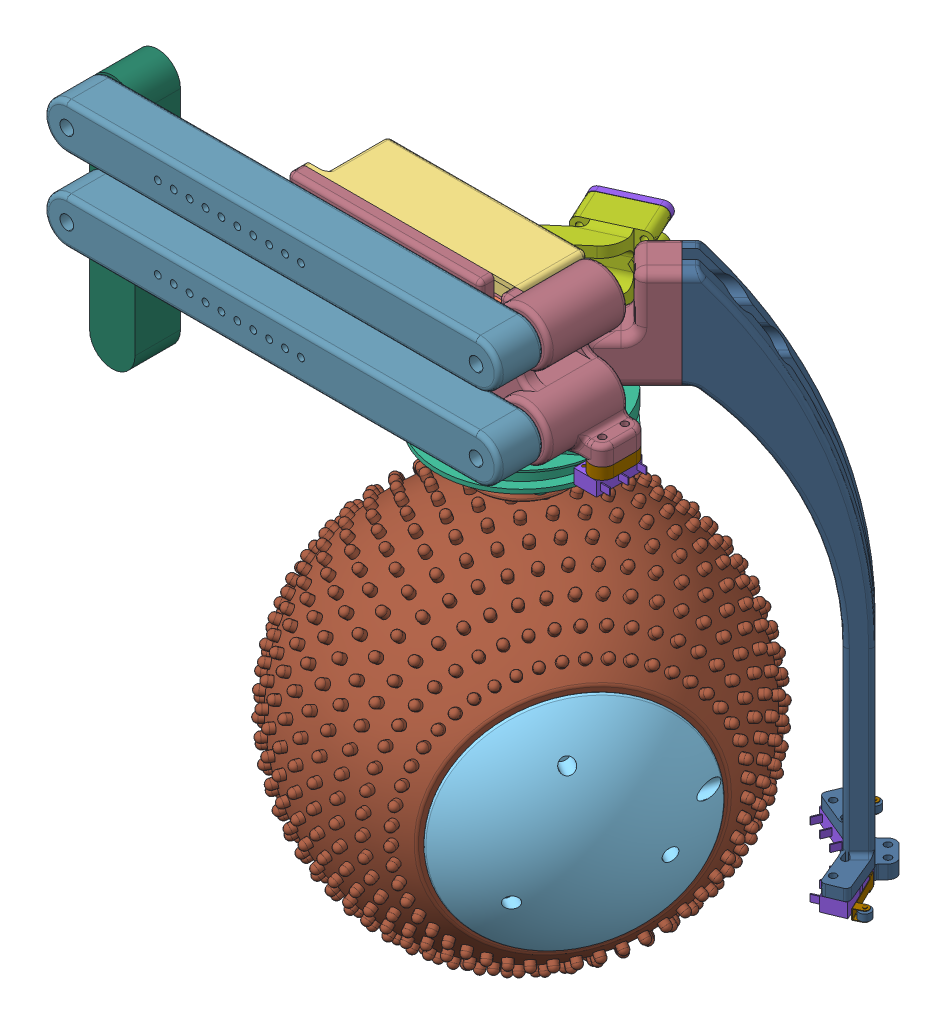
SolidWorks assembly _OmniWheel, configuration Default. Lengths in mm.
Overall size (257.35 285.35 230.93).
42 component instances, 28 part files, 105 mates.
Components (placement in the parent):
- 10mmThreadedRod-1: 10mmThreadedRod [Default] at (71.9678 -158.25 -77.1045) x (0.033468 -0.997752 -0.058051) z (0.498338 0.067008 -0.864389) size (9.53 70 9.53)
- arduino-1: arduino [Valor predeterminado] at (148.41 -2.75 -21) x (-1 0 0) z (0 0 -1) size (45.18 4.5 17.78)
- DriveMotor-1: DriveMotor [Default] at (153.4035 -158.25 -30.1552) x (-0.264151 0.848701 0.458182) z (0.423893 0.528873 -0.735261) size (25 86.5 25)
- hollowThreadedNut-1: hollowThreadedNut [Default] at (110.5631 -158.25 -54.8536) x (-0.092382 -0.982745 0.16024) z (0.490843 -0.184963 -0.851388) size (16.17 2.5 14)
- L298N Motor Driver arduino-1: L298N Motor Driver arduino [Default] at (96.25 -2.5 -9.5) x (0 1 0) z (-1 0 0) size (43.5 26 43.5)
- n20 m4x55 encoder v2-1: n20 m4x55 encoder v2 [Default] at (131.4749 -29.5 -92.3762) x (-0.417468 0 -0.908691) z (0 -1 0) size (12 10 42.21)
- slip_ring-1: slip_ring [Default] at (145 -53 -35) x (0.999063 0 0.043268) z (-0.043268 0 0.999063) size (23.5 17.5 23.5)
- switch_body-1: switch_body [Default] at (198 -38.125 -25) x (0 0 -1) z (0 1 0) size (20 14 6.25)
- switch_lever-1: switch_lever [Default] at (187.7929 -38.125 -26.5353) x (0.019708 0 -0.999806) z (0 1 0) size (20 8.75 6)
- switch_wheel-1: switch_wheel [Default] at (184.3312 -38 -34.8551) x (-0.999947 0 -0.010277) z (0 1 0) size (5 5 3)
- sphere_wheel-1: sphere_wheel [Default] at (145 -158.25 -35) x (-0.866337 0 -0.499461) z (0.492131 0.170683 -0.853624) size (125.5 168 168)
- motorMount-1: motorMount [Default] at (130.9004 -158.25 -43.1287) x (0.446555 -0.447916 -0.77457) z (-0.223716 -0.894076 0.388046) size (31.75 83.44 31.75)
- hollowThreadedNut-2: hollowThreadedNut [Default] at (123.7314 -158.25 -47.2618) x (-0.092382 -0.982745 0.16024) z (0.490843 -0.184963 -0.851388) size (16.17 2.5 14)
- hollowThreadedNut-4: hollowThreadedNut [Default] at (71.1448 -158.25 -77.579) x (0.01495 -0.999552 -0.025931) z (0.499237 0.029932 -0.865948) size (16.17 2.5 14)
- hollowThreadedNut-5: hollowThreadedNut [Default] at (87.172 -158.25 -68.339) x (0.24973 -0.866025 -0.433168) z (0.432546 0.5 -0.75027) size (16.17 2.5 14)
- suspension_mount-1: suspension_mount [Default] at (145 -30 -35) x (0 0 1) z (0 1 0) size (77.43 128.5 61.17)
- suspension_bar-1: suspension_bar [Default] at (180 18 10) size (200 20 20)
- suspension_mount_body-1: suspension_mount_body [Default] at origin size (20 111.88 20)
- bearing2-1: bearing2 [Default] at (106.448 -158.25 -57.226) x (0.296277 0.805059 -0.513906) z (0.402095 -0.593194 -0.697452) size (25 7 25)
- Wheel_cap-1: Wheel_cap [Default] at (109.4802 -158.25 -55.4779) x (0.08525 -0.985326 -0.147869) z (0.492131 0.170683 -0.853624) size (59.5 22.5 59.5)
- washer1-1: washer1 [Default] at (101.1417 -158.25 -60.2852) x (-0.362018 -0.68894 0.627937) z (0.344098 -0.724818 -0.596854) size (25 2.25 25)
- SpongeRing-1: SpongeRing [Default] at (96.052 -158.25 -63.2195) x (-0.866337 0 -0.499461) z (0.488344 -0.20981 -0.847054) size (14 51.5 51.5)
- wheel_arm-1: wheel_arm [Default] at (87.8218 -158.25 -67.9644) x (-0.866337 0 -0.499461) z (0.499461 0 -0.866337) size (108.38 170.79 80.42)
- suspension_bar-3: suspension_bar [Default] at (180 -18 10) size (200 20 20)
- suspension_mount_lid-1: suspension_mount_lid [Default] at (120 -2.5 -39) x (1 0 0) z (0 0 -1) size (96 55 30)
- bearing3-1: bearing3 [Default] at (145 -37.25 -35) x (0.997463 0 -0.071184) z (0 -1 0) size (28.5 28.5 9.5)
- 10mmThreadedRod-2: 10mmThreadedRod [short] at (145 -15 -35) x (0.211057 0 0.977474) z (-0.977474 0 0.211057) size (9.53 36 9.53)
- hollowThreadedNut-6: hollowThreadedNut [Default] at (145 -11.75 -35) x (-0.864079 0 0.503356) z (0.503356 0 0.864079) size (16.17 2.5 14)
- hollowThreadedNut-7: hollowThreadedNut [Default] at (145 -31.25 -35) x (-0.864079 0 0.503356) z (0.503356 0 0.864079) size (16.17 2.5 14)
- hollowThreadedNut-8: hollowThreadedNut [Default] at (145 -43.25 -35) x (-0.864079 0 0.503356) z (0.503356 0 0.864079) size (16.17 2.5 14)
- wheel_cap_2-1: wheel_cap_2 [Default] at (144.7834 -158.25 -35.1249) x (0.866337 0 0.499461) z (-0.08525 0.985326 0.147869) size (17.75 96.67 96.67)
- large_timing_pully-1: large_timing_pully [Default] at (145 -43 -35) x (-0.866337 0 -0.499461) z (0.499461 0 -0.866337) size (73.67 25.42 73.67)
- micro_gear_motor_casing_A-1: micro_gear_motor_casing_A [Default] at (131.4529 -22 -92.3705) x (-0.417468 0 -0.908691) z (0.908691 0 -0.417468) size (33.5 37.27 49.25)
- micro_gear_motor_casing_B-1: micro_gear_motor_casing_B [Default] at (128.2175 -22 -99.4128) x (-0.908691 0 0.417468) z (-0.417468 0 -0.908691) size (28.5 37.25 3)
- switch_spacer-1: switch_spacer [Default] at (195.5 -32.5 -25) x (0 0 -1) z (1 0 0) size (20 5 10)
- sensorArray_frame-1: sensorArray_frame [Default] at (180.3553 -7.5 -70.3553) x (-0.707107 0 0.707107) z (-0.707107 0 -0.707107) size (67.99 233.5 54.5)
- switch_body-2: switch_body [Default] at (202.791 -215.625 -113.7167) x (-0.92388 0 -0.382683) z (0 -1 0) size (20 14 6.25)
- switch_lever-2: switch_lever [Default] at (206.7215 -215.625 -125.3908) x (-0.810364 0 -0.585927) z (0 -1 0) size (20 8.75 6)
- switch_wheel-2: switch_wheel [Default] at (202.16 -215.625 -133.1622) x (0.999993 0 -0.003676) z (0 -1 0) size (5 5 3)
- switch_body-3: switch_body [Default] at (223.7167 -215.625 -92.791) x (0.382683 0 0.92388) z (0 1 0) size (20 14 6.25)
- switch_lever-3: switch_lever [Default] at (234.3073 -215.625 -95.6971) x (0.439028 0 0.898473) z (0 1 0) size (20 8.75 6)
- switch_wheel-3: switch_wheel [Default] at (241.1863 -215.625 -89.8762) x (-0.999993 0 -0.003746) z (0 1 0) size (5 5 3)
Mates (geometry in assembly coordinates):
- Concentric1: concentric aligned: cylinder of DriveMotor-1 through (197.1535 -158.25 -4.9325) axis (-0.866337 0 -0.499461) radius 12.5; cylinder of sphere_wheel-1 through (208.2426 -158.25 1.4606) axis (-0.866337 0 -0.499461) radius 25
- Concentric2: concentric aligned: cylinder of DriveMotor-1 through (173.7624 -158.25 -18.4179) axis (-0.866337 0 -0.499461) radius 12.2; cylinder of motorMount-1 through (183.9323 -158.25 -12.5547) axis (-0.866337 0 -0.499461) radius 12.7
- Concentric4: concentric aligned: cylinder of 10mmThreadedRod-1 through (15.6559 -158.25 -109.5695) axis (0.866337 0 0.499461) radius 4.7625; cylinder of motorMount-1 through (111.646 -158.25 -54.2292) axis (0.866337 0 0.499461) radius 4.7625
- Concentric5: concentric aligned: cylinder of 10mmThreadedRod-1 through (15.6559 -158.25 -109.5695) axis (0.866337 0 0.499461) radius 4.7625; cylinder of hollowThreadedNut-1 through (109.4802 -158.25 -55.4779) axis (0.866337 0 0.499461) radius 5
- Concentric6: concentric aligned: cylinder of 10mmThreadedRod-1 through (15.6559 -158.25 -109.5695) axis (0.866337 0 0.499461) radius 4.7625; cylinder of hollowThreadedNut-2 through (122.6485 -158.25 -47.8861) axis (0.866337 0 0.499461) radius 5
- Coincident1: coincident anti-aligned: plane of motorMount-1 through (122.6485 -158.25 -47.8861) normal (0.866337 0 0.499461); plane of hollowThreadedNut-2 through (122.6485 -158.25 -47.8861) normal (-0.866337 0 -0.499461)
- Coincident2: coincident anti-aligned: plane of hollowThreadedNut-1 through (111.646 -158.25 -54.2292) normal (0.866337 0 0.499461); plane of motorMount-1 through (111.646 -158.25 -54.2292) normal (-0.866337 0 -0.499461)
- Concentric9: concentric aligned: cylinder of 10mmThreadedRod-1 through (15.6559 -158.25 -109.5695) axis (0.866337 0 0.499461) radius 4.7625; cylinder of hollowThreadedNut-4 through (70.0619 -158.25 -78.2033) axis (0.866337 0 0.499461) radius 5
- Concentric10: concentric aligned: cylinder of 10mmThreadedRod-1 through (15.6559 -158.25 -109.5695) axis (0.866337 0 0.499461) radius 4.7625; cylinder of hollowThreadedNut-5 through (86.0891 -158.25 -68.9633) axis (0.866337 0 0.499461) radius 5
- Concentric11: concentric aligned: cylinder of switch_body-1 through (189.5 -35 -18) axis (0 -1 0) radius 0.75; cylinder of switch_lever-1 through (189.5 -36.125 -18) axis (0 -1 0) radius 1.5
- Width1: width anti-aligned: plane of switch_body-1 through (198 -41.25 -25) normal (0 -1 0); plane of switch_lever-1 through (198 -35 -25) normal (0 1 0); plane of switch_body-1 through (187.7799 -40.875 -19.5342) normal (0 1 0); plane of switch_lever-1 through (187.7799 -35.375 -19.5342) normal (0 -1 0)
- Concentric12: concentric aligned: cylinder of switch_lever-1 through (184.3312 -35.625 -34.8551) axis (0 -1 0) radius 0.75; cylinder of switch_wheel-1 through (184.3312 -36.5 -34.8551) axis (0 -1 0) radius 2.5
- Concentric18: concentric anti-aligned: cylinder of 10mmThreadedRod-1 through (15.6559 -158.25 -109.5695) axis (0.866337 0 0.499461) radius 4.7625; cylinder of bearing2-1 through (109.4802 -158.25 -55.4779) axis (-0.866337 0 -0.499461) radius 5
- Coincident24: coincident anti-aligned: plane of hollowThreadedNut-1 through (109.4802 -158.25 -55.4779) normal (-0.866337 0 -0.499461); plane of bearing2-1 through (109.4802 -158.25 -55.4779) normal (0.866337 0 0.499461)
- Concentric19: concentric anti-aligned: cylinder of bearing2-1 through (109.4802 -158.25 -55.4779) axis (-0.866337 0 -0.499461) radius 11; cylinder of Wheel_cap-1 through (89.9876 -158.25 -66.7157) axis (0.866337 0 0.499461) radius 11.125
- Coincident25: coincident anti-aligned: plane of bearing2-1 through (108.1807 -158.25 -56.2271) normal (-0.866337 0 -0.499461); plane of Wheel_cap-1 through (108.1807 -158.25 -56.2271) normal (0.866337 0 0.499461)
- Parallel1: parallel anti-aligned: plane of sphere_wheel-1 through (145 -158.25 -35) normal (-0.08525 0.985326 0.147869); plane of Wheel_cap-1 through (109.4802 -158.25 -55.4779) normal (0.08525 -0.985326 -0.147869)
- Concentric20: concentric aligned: cylinder of 10mmThreadedRod-1 through (15.6559 -158.25 -109.5695) axis (0.866337 0 0.499461) radius 4.7625; cylinder of washer1-1 through (100.1671 -158.25 -60.8471) axis (0.866337 0 0.499461) radius 5.75
- Coincident26: coincident anti-aligned: plane of Wheel_cap-1 through (102.1163 -158.25 -59.7233) normal (-0.866337 0 -0.499461); plane of washer1-1 through (102.1163 -158.25 -59.7233) normal (0.866337 0 0.499461)
- Tangent1: tangent anti-aligned: cylinder of Wheel_cap-1 through (120.2231 -153.172 -83.1216) axis (-0.492131 -0.170683 0.853624) radius 4; plane of SpongeRing-1 through (103.5834 -144.5616 -62.268) normal (0.866337 0 0.499461)
- Concentric21: concentric aligned: cylinder of Wheel_cap-1 through (107.3144 -158.25 -56.7265) axis (-0.866337 0 -0.499461) radius 26; cylinder of SpongeRing-1 through (96.052 -158.25 -63.2195) axis (-0.866337 0 -0.499461) radius 25.75
- Concentric22: concentric aligned: cylinder of 10mmThreadedRod-1 through (15.6559 -158.25 -109.5695) axis (0.866337 0 0.499461) radius 4.7625; cylinder of wheel_arm-1 through (75.6931 -158.25 -74.9568) axis (0.866337 0 0.499461) radius 4.7625
- Concentric24: concentric: sphere of sphere_wheel-1; sphere of wheel_arm-1
- Parallel2: parallel anti-aligned: plane of hollowThreadedNut-5 through (84.0706 -151.25 -65.4621) normal (0 1 0); plane of wheel_arm-1 through (88.1437 -151.125 -72.5271) normal (0 -1 0)
- Coincident27: coincident anti-aligned: plane of hollowThreadedNut-5 through (86.0891 -158.25 -68.9633) normal (-0.866337 0 -0.499461); plane of wheel_arm-1 through (86.0891 -158.25 -68.9633) normal (0.866337 0 0.499461)
- Concentric26: concentric anti-aligned: cylinder of slip_ring-1 through (145 -61.75 -35) axis (0 -1 0) radius 6.25; cylinder of wheel_arm-1 through (145 -66.25 -35) axis (0 1 0) radius 20
- Distance2: distance = 12 mm anti-aligned: plane of DriveMotor-1 through (133.0446 -158.25 -41.8926) normal (-0.866337 0 -0.499461); plane of motorMount-1 through (122.6485 -158.25 -47.8861) normal (0.866337 0 0.499461)
- Coincident28: coincident anti-aligned: plane of hollowThreadedNut-4 through (72.2277 -158.25 -76.9547) normal (0.866337 0 0.499461); plane of wheel_arm-1 through (72.2277 -158.25 -76.9547) normal (-0.866337 0 -0.499461)
- Distance3: distance = 4 mm aligned: plane of hollowThreadedNut-2 through (124.8144 -158.25 -46.6374) normal (0.866337 0 0.499461); plane of 10mmThreadedRod-1 through (128.2797 -158.25 -44.6396) normal (0.866337 0 0.499461)
- Coincident30: coincident anti-aligned: plane of slip_ring-1 through (133.261 -48.25 -35.5084) normal (0 -1 0); plane of wheel_arm-1 through (145 -48.25 -35) normal (0 1 0)
- Concentric28: concentric anti-aligned: cylinder of suspension_mount-1 through (145 30 -35) axis (0 -1 0) radius 20; cylinder of wheel_arm-1 through (145 -66.25 -35) axis (0 1 0) radius 20
- Parallel4: parallel aligned: cylinder of n20 m4x55 encoder v2-1 through (131.4529 -32.9733 -92.3705) axis (0 -1 0) radius 1.954; cylinder of suspension_mount-1 through (145 30 -35) axis (0 -1 0) radius 20
- Parallel5: parallel aligned: plane of suspension_mount-1 through (145 -30 -35) normal (0 0 1)
- Concentric33: concentric aligned: cylinder of suspension_mount-1 through (180 18 -15) axis (0 0 -1) radius 3; cylinder of suspension_bar-1 through (180 18 20) axis (0 0 -1) radius 3
- Coincident32: coincident aligned: plane of suspension_bar-1 through (0 18 20) normal (0 0 1); plane of suspension_bar-3 through (0 -18 20) normal (0 0 1)
- Concentric42: concentric aligned: cylinder of suspension_mount-1 through (180 -18 -15) axis (0 0 -1) radius 3; cylinder of suspension_bar-3 through (180 -18 20) axis (0 0 -1) radius 3
- Coincident33: coordinate: point of suspension_mount_body-1
- Concentric45: concentric anti-aligned: cylinder of suspension_bar-1 through (0 18 20) axis (0 0 -1) radius 3; cylinder of suspension_mount_body-1 through (0 18 -20) axis (0 0 1) radius 3
- Concentric46: concentric anti-aligned: cylinder of suspension_mount_body-1 through (0 -18 -20) axis (0 0 1) radius 3; cylinder of suspension_bar-3 through (0 -18 20) axis (0 0 -1) radius 3
- Coincident34: coincident anti-aligned: plane of suspension_mount-1 through (180 18 0) normal (0 0 1); plane of suspension_bar-1 through (0 18 0) normal (0 0 -1)
- Coincident35: coincident anti-aligned: plane of suspension_mount_body-1 through (0 18 0) normal (0 0 1); plane of suspension_bar-3 through (0 -18 0) normal (0 0 -1)
- Parallel8: parallel aligned: plane of L298N Motor Driver arduino-1 through (96.25 -2.5 -11) normal (0 0 -1); plane of suspension_mount-1 through (180 18 -7) normal (0 0 -1)
- Parallel9: parallel aligned: plane of L298N Motor Driver arduino-1 through (74.5 -24.25 -11) normal (0 -1 0); plane of suspension_mount-1 through (145 -30 -35) normal (0 -1 0)
- Parallel11: parallel aligned: plane of arduino-1 through (148.41 -1.75 -21) normal (0 1 0); plane of suspension_mount-1 through (168 -10 -55) normal (0 1 0)
- Concentric47: concentric anti-aligned: cylinder of L298N Motor Driver arduino-1 through (115 16.25 -11) axis (0 0 1) radius 1.5; cylinder of suspension_mount-1 through (115 16.25 0) axis (0 0 -1) radius 1.5
- Concentric48: concentric anti-aligned: cylinder of L298N Motor Driver arduino-1 through (77.5 -21.25 -11) axis (0 0 1) radius 1.5; cylinder of suspension_mount-1 through (77.5 -21.25 0) axis (0 0 -1) radius 1.5
- Coincident36: coincident anti-aligned: plane of L298N Motor Driver arduino-1 through (96.25 -2.5 -9.5) normal (0 0 1); plane of suspension_mount-1 through (77.5 -21.25 -9.5) normal (0 0 -1)
- Width3: width anti-aligned: plane of suspension_mount-1 through (170 -3.5 -30) normal (0 0 1); plane of suspension_mount-1 through (170 -3.5 -12) normal (0 0 -1); plane of arduino-1 through (170 -1.75 -29.89) normal (0 0 -1); plane of arduino-1 through (170 -1.75 -12.11) normal (0 0 1)
- Coincident37: coincident anti-aligned: plane of arduino-1 through (170 -1.75 -29.89) normal (1 0 0); plane of suspension_mount-1 through (170 -30 -35) normal (-1 0 0)
- Width4: width aligned: plane of suspension_mount-1 through (192 -2.25 -25.25) normal (0 1 0); plane of suspension_mount-1 through (192 2.25 -25.25) normal (0 -1 0); plane of arduino-1 through (148.41 1.75 -21) normal (0 1 0); plane of arduino-1 through (148.41 -1.75 -21) normal (0 -1 0)
- Coincident38: coincident aligned: plane of suspension_mount-1 through (170.2532 25 -7) normal (0 1 0); plane of suspension_mount_lid-1 through (72 25 -41) normal (0 1 0)
- Coincident39: coincident aligned: plane of suspension_mount-1 through (72 25 -7) normal (-1 0 0); plane of suspension_mount_lid-1 through (72 25 -41) normal (-1 0 0)
- Coincident40: coincident anti-aligned: plane of suspension_mount-1 through (161 15 -11) normal (0 0 -1); plane of suspension_mount_lid-1 through (120 -2.5 -11) normal (0 0 1)
- Concentric49: concentric aligned: cylinder of wheel_arm-1 through (145 -66.25 -35) axis (0 1 0) radius 20; cylinder of bearing3-1 through (145 -42 -35) axis (0 1 0) radius 14.25
- Concentric50: concentric anti-aligned: cylinder of suspension_mount-1 through (145 -30 -35) axis (0 1 0) radius 4.7625; cylinder of 10mmThreadedRod-2 through (145 50 -35) axis (0 -1 0) radius 4.7625
- Concentric51: concentric anti-aligned: cylinder of 10mmThreadedRod-2 through (145 50 -35) axis (0 -1 0) radius 4.7625; cylinder of hollowThreadedNut-6 through (145 -13 -35) axis (0 1 0) radius 5
- Coincident42: coincident anti-aligned: plane of suspension_mount-1 through (145 -13 -35) normal (0 1 0); plane of hollowThreadedNut-6 through (145 -13 -35) normal (0 -1 0)
- Coincident43: coincident aligned: plane of suspension_mount-1 through (168 -10 -55) normal (0 1 0); plane of 10mmThreadedRod-2 through (159.2034 -10 -42.9391) normal (0 1 0)
- Concentric52: concentric anti-aligned: cylinder of 10mmThreadedRod-2 through (145 50 -35) axis (0 -1 0) radius 4.7625; cylinder of hollowThreadedNut-7 through (145 -32.5 -35) axis (0 1 0) radius 5
- Coincident44: coincident anti-aligned: plane of suspension_mount-1 through (145 -30 -35) normal (0 -1 0); plane of hollowThreadedNut-7 through (145 -30 -35) normal (0 1 0)
- Coincident45: coincident anti-aligned: plane of bearing3-1 through (145 -32.5 -35) normal (0 1 0); plane of hollowThreadedNut-7 through (145 -32.5 -35) normal (0 -1 0)
- Concentric53: concentric anti-aligned: cylinder of 10mmThreadedRod-2 through (145 50 -35) axis (0 -1 0) radius 4.7625; cylinder of hollowThreadedNut-8 through (145 -44.5 -35) axis (0 1 0) radius 5
- Coincident46: coincident anti-aligned: plane of bearing3-1 through (145 -42 -35) normal (0 -1 0); plane of hollowThreadedNut-8 through (145 -42 -35) normal (0 1 0)
- Coincident47: coincident anti-aligned: plane of wheel_arm-1 through (127.6535 -42 -39.8063) normal (0 1 0); plane of bearing3-1 through (145 -42 -35) normal (0 -1 0)
- Coincident48: coincident anti-aligned: plane of sphere_wheel-1 through (198.7129 -158.25 -4.0334) normal (0.866337 0 0.499461); plane of wheel_cap_2-1 through (223.4419 -149.6734 -46.927) normal (-0.866337 0 -0.499461)
- Concentric54: concentric aligned: cylinder of sphere_wheel-1 through (208.2426 -158.25 1.4606) axis (-0.866337 0 -0.499461) radius 25; cylinder of wheel_cap_2-1 through (211.7079 -158.25 3.4585) axis (-0.866337 0 -0.499461) radius 2
- Parallel12: parallel aligned: plane of sphere_wheel-1 through (145 -158.25 -35) normal (-0.08525 0.985326 0.147869); plane of wheel_cap_2-1 through (144.7834 -158.25 -35.1249) normal (-0.08525 0.985326 0.147869)
- Concentric55: concentric anti-aligned: cylinder of wheel_arm-1 through (145 -66.25 -35) axis (0 1 0) radius 20; cylinder of large_timing_pully-1 through (145 -43 -35) axis (0 -1 0) radius 20.25
- Parallel13: parallel aligned: plane of wheel_arm-1 through (87.8218 -158.25 -67.9644) normal (0.499461 0 -0.866337); plane of large_timing_pully-1 through (145 -43 -35) normal (0.499461 0 -0.866337)
- Parallel14: parallel aligned: plane of n20 m4x55 encoder v2-1 through (129.4363 -29.5 -84.8367) normal (-0.908691 0 0.417468); plane of micro_gear_motor_casing_A-1 through (133.6143 -5.5 -100.2415) normal (-0.908691 0 0.417468)
- Concentric58: concentric anti-aligned: cylinder of n20 m4x55 encoder v2-1 through (131.4529 -32.9733 -92.3705) axis (0 -1 0) radius 1.954; cylinder of micro_gear_motor_casing_A-1 through (131.4529 -42.7361 -92.3705) axis (0 1 0) radius 6.4971
- Coincident49: coincident anti-aligned: plane of n20 m4x55 encoder v2-1 through (131.4749 -38.5 -92.3762) normal (0 -1 0); plane of micro_gear_motor_casing_A-1 through (131.4529 -38.5 -92.3705) normal (0 1 0)
- Distance4: distance = 3.5 mm aligned: plane of wheel_arm-1 through (127.6535 -32 -39.8063) normal (0 1 0); plane of large_timing_pully-1 through (127.4567 -35.5 -45.1141) normal (0 1 0)
- Concentric59: concentric anti-aligned: cylinder of micro_gear_motor_casing_A-1 through (125.1286 -37.125 -80.386) axis (-0.417468 0 -0.908691) radius 1.4; cylinder of micro_gear_motor_casing_B-1 through (117.8229 -37.125 -96.2881) axis (0.417468 0 0.908691) radius 1.5
- Concentric60: concentric anti-aligned: cylinder of micro_gear_motor_casing_A-1 through (144.6654 -6.875 -89.3616) axis (-0.417468 0 -0.908691) radius 1.4; cylinder of micro_gear_motor_casing_B-1 through (137.3597 -6.875 -105.2637) axis (0.417468 0 0.908691) radius 1.5
- Coincident50: coincident anti-aligned: plane of micro_gear_motor_casing_A-1 through (135.4317 -5.5 -101.0764) normal (-0.417468 0 -0.908691); plane of micro_gear_motor_casing_B-1 through (138.6121 -13.875 -102.5376) normal (0.417468 0 0.908691)
- Coincident51: coincident anti-aligned: plane of sphere_wheel-1 through (106.9227 -128.6902 -51.0418) normal (-0.866337 0 -0.499461); plane of Wheel_cap-1 through (109.4802 -158.25 -55.4779) normal (0.866337 0 0.499461)
- Concentric61: concentric aligned: cylinder of suspension_mount-1 through (113.4808 -25 -59.628) axis (0 1 0) radius 2; cylinder of micro_gear_motor_casing_A-1 through (113.4808 -30 -59.628) axis (0 1 0) radius 2
- Width5: width aligned: plane of suspension_mount-1 through (168 -10 -55) normal (0 1 0); plane of suspension_mount-1 through (145 -25 -35) normal (0 -1 0); plane of micro_gear_motor_casing_A-1 through (131.4529 -25.25 -92.3705) normal (0 1 0); plane of micro_gear_motor_casing_A-1 through (131.4529 -9.75 -92.3705) normal (0 -1 0)
- Concentric62: concentric aligned: cylinder of switch_body-1 through (195.5 -35 -30) axis (0 -1 0) radius 1.5; cylinder of suspension_mount-1 through (195.5 -22 -30) axis (0 -1 0) radius 1.5
- Concentric63: concentric aligned: cylinder of switch_body-1 through (195.5 -35 -20) axis (0 -1 0) radius 1.5; cylinder of suspension_mount-1 through (195.5 -22 -20) axis (0 -1 0) radius 1.5
- Concentric64: concentric aligned: cylinder of suspension_mount-1 through (195.5 -22 -20) axis (0 -1 0) radius 1.5; cylinder of switch_spacer-1 through (195.5 -30 -20) axis (0 -1 0) radius 1.6
- Concentric65: concentric aligned: cylinder of suspension_mount-1 through (195.5 -22 -30) axis (0 -1 0) radius 1.5; cylinder of switch_spacer-1 through (195.5 -30 -30) axis (0 -1 0) radius 1.6
- Coincident52: coincident anti-aligned: plane of suspension_mount-1 through (145 -30 -35) normal (0 -1 0); plane of switch_spacer-1 through (195.5 -30 -30) normal (0 1 0)
- Coincident53: coincident anti-aligned: plane of switch_body-1 through (198 -35 -25) normal (0 1 0); plane of switch_spacer-1 through (195.5 -35 -30) normal (0 -1 0)
- PathMate2: path: circle of switch_wheel-1; curve of large_timing_pully-1
- PathMate3: path: unknown of switch_wheel-1; edge_curve of large_timing_pully-1
- Coincident54: coincident anti-aligned: plane of suspension_mount-1 through (187.4264 -30 -63.2843) normal (0.707107 0 -0.707107); plane of sensorArray_frame-1 through (173.2843 -30 -77.4264) normal (-0.707107 0 0.707107)
- Width6: width aligned: plane of sensorArray_frame-1 through (116.7157 -128.3616 -20.8579) normal (-0.707107 0 -0.707107); plane of suspension_mount-1 through (130.8579 -128.3616 -6.7157) normal (0.707107 0 0.707107); plane of sensorArray_frame-1 through (150.1764 -30 -54.3185) normal (-0.707107 0 -0.707107); plane of suspension_mount-1 through (164.3185 -30 -40.1764) normal (0.707107 0 0.707107)
- Coincident56: coincident aligned: plane of suspension_mount-1 through (176.8198 15 -52.6777) normal (0 1 0); plane of sensorArray_frame-1 through (173.2843 15 -77.4264) normal (0 1 0)
- Concentric66: concentric aligned: cylinder of switch_body-2 through (212.511 -218.75 -118.8909) axis (0 1 0) radius 0.75; cylinder of switch_lever-2 through (212.511 -218.375 -118.8909) axis (0 1 0) radius 1.5
- Concentric67: concentric aligned: cylinder of switch_lever-2 through (202.16 -218.125 -133.1622) axis (0 1 0) radius 0.75; cylinder of switch_wheel-2 through (202.16 -217.125 -133.1622) axis (0 1 0) radius 2.5
- Width7: width aligned: plane of switch_lever-2 through (201.3809 -217.875 -129.098) normal (0 -1 0); plane of switch_wheel-2 through (201.3809 -213.375 -129.098) normal (0 1 0); plane of switch_lever-2 through (202.16 -217.125 -133.1622) normal (0 -1 0); plane of switch_wheel-2 through (202.16 -214.125 -133.1622) normal (0 1 0)
- Width8: width anti-aligned: plane of switch_body-2 through (202.791 -212.5 -113.7167) normal (0 1 0); plane of switch_lever-2 through (202.791 -218.75 -113.7167) normal (0 -1 0); plane of switch_body-2 through (212.3208 -212.875 -121.188) normal (0 -1 0); plane of switch_lever-2 through (212.3208 -218.375 -121.188) normal (0 1 0)
- Coincident57: coincident anti-aligned: plane of sensorArray_frame-1 through (208.6396 -212.5 -112.7817) normal (0 -1 0); plane of switch_body-2 through (202.791 -212.5 -113.7167) normal (0 1 0)
- Parallel15: parallel aligned: plane of sensorArray_frame-1 through (193.5522 -207.5 -117.5436) normal (-0.382683 0 0.92388); plane of switch_body-2 through (193.5522 -218.75 -117.5436) normal (-0.382683 0 0.92388)
- Coincident58: coincident aligned: plane of sensorArray_frame-1 through (197.3791 -207.5 -126.7824) normal (-0.92388 0 -0.382683); plane of switch_body-2 through (197.1877 -218.75 -126.3204) normal (-0.92388 0 -0.382683)
- Coincident59: coincident aligned: plane of sensorArray_frame-1 through (216.476 -207.5 -118.8721) normal (0.382683 0 -0.92388); plane of switch_body-2 through (215.8566 -218.75 -119.1287) normal (0.382683 0 -0.92388)
- Concentric68: concentric aligned: cylinder of switch_lever-3 through (241.1863 -213.125 -89.8762) axis (0 -1 0) radius 0.75; cylinder of switch_wheel-3 through (241.1863 -214.125 -89.8762) axis (0 -1 0) radius 2.5
- Width9: width aligned: plane of switch_lever-3 through (237.0487 -213.375 -89.8022) normal (0 1 0); plane of switch_wheel-3 through (237.0487 -217.875 -89.8022) normal (0 -1 0); plane of switch_lever-3 through (241.1863 -214.125 -89.8762) normal (0 1 0); plane of switch_wheel-3 through (241.1863 -217.125 -89.8762) normal (0 -1 0)
- Concentric69: concentric aligned: cylinder of switch_body-3 through (228.8909 -212.5 -102.511) axis (0 -1 0) radius 0.75; cylinder of switch_lever-3 through (228.8909 -213.625 -102.511) axis (0 -1 0) radius 1.5
- Width10: width aligned: plane of switch_body-3 through (223.7167 -218.75 -92.791) normal (0 -1 0); plane of switch_lever-3 through (223.7167 -212.5 -92.791) normal (0 1 0); plane of switch_body-3 through (228.2018 -218.625 -100.5047) normal (0 -1 0); plane of switch_lever-3 through (228.2018 -212.625 -100.5047) normal (0 1 0)
- Coincident60: coincident anti-aligned: plane of sensorArray_frame-1 through (208.6396 -212.5 -112.7817) normal (0 -1 0); plane of switch_body-3 through (223.7167 -212.5 -92.791) normal (0 1 0)
- Concentric70: concentric aligned: cylinder of sensorArray_frame-1 through (224.113 -207.5 -98.3671) axis (0 -1 0) radius 1.5; cylinder of switch_body-3 through (224.113 -212.5 -98.3671) axis (0 -1 0) radius 1.5
- Concentric71: concentric aligned: cylinder of sensorArray_frame-1 through (227.9399 -207.5 -89.1283) axis (0 -1 0) radius 1.5; cylinder of switch_body-3 through (227.9399 -212.5 -89.1283) axis (0 -1 0) radius 1.5
